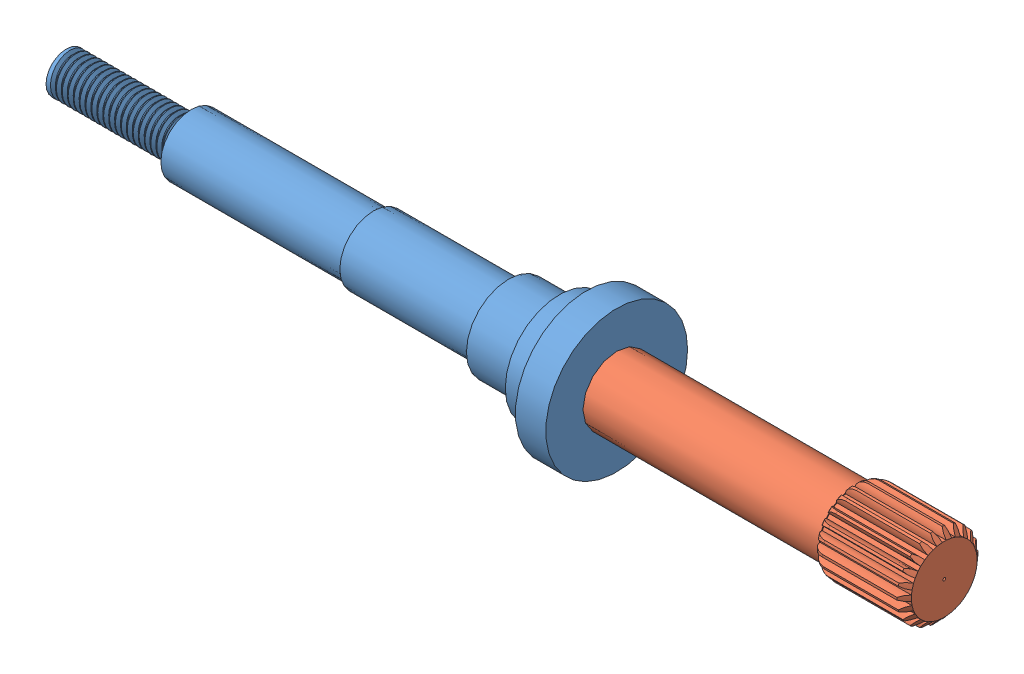
SolidWorks assembly Driveshaft1, configuration Default. Lengths in mm.
Overall size (260 42 42).
2 component instances, 2 part files, 2 mates.
Components (placement in the parent):
- Part3-1: Part3 [Default] at (-24.3067 3.1852 4.5982) x (0 -1 0) z (0 0 1) size (42 163 42)
- spur gear_new-4: spur gear_new [ISO - Spur gear 1M 22T 14.5PA 27FW ---S22B20H67L0.8N] at (54.6933 3.1852 4.5982) size (97 23.96 24.03)
Mates (geometry in assembly coordinates):
- Concentric2: concentric anti-aligned: circle of Part3-1; circle of spur gear_new-4
- Coincident3: coincident anti-aligned: plane of Part3-1 through (-15.3067 3.1852 4.5982) normal (1 0 0); plane of spur gear_new-4 through (-15.3067 3.1852 4.5982) normal (-1 0 0)
